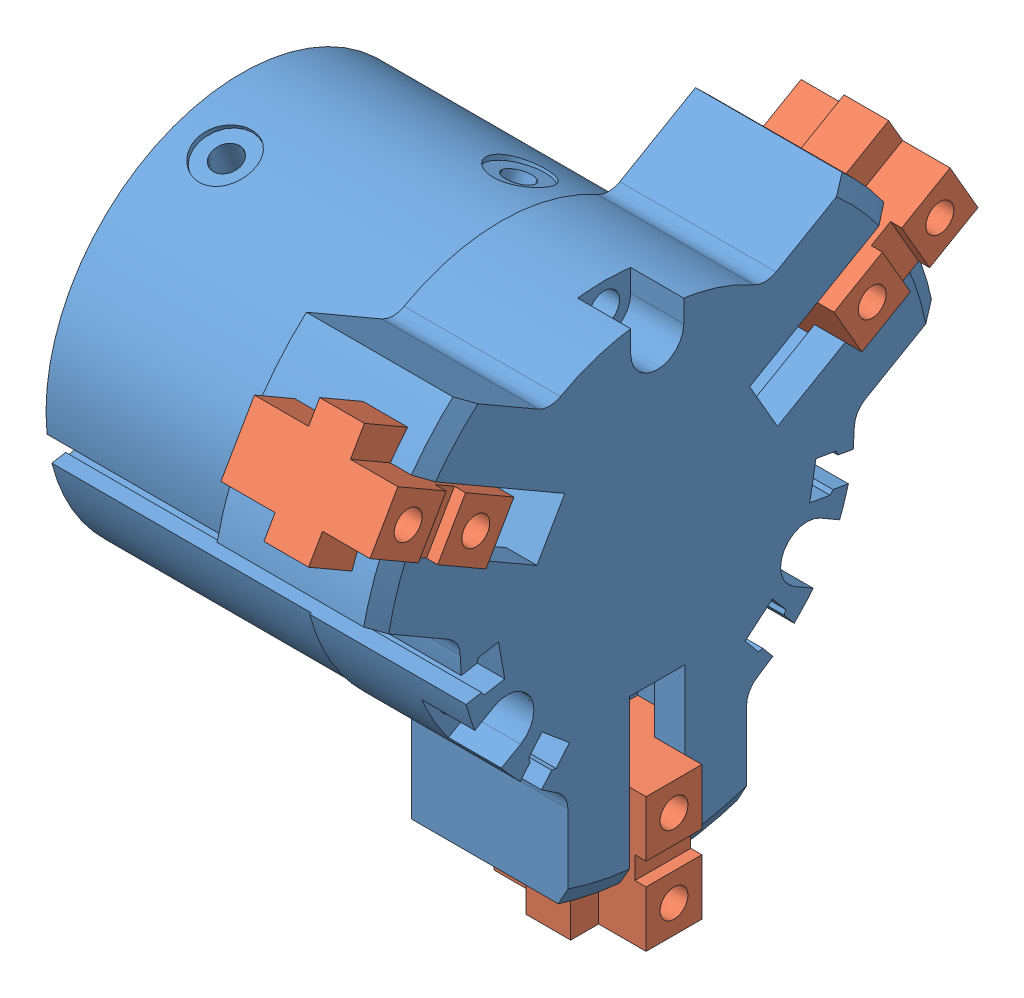
SolidWorks assembly MHSL3-50D, configuration MHSL3-50D. Lengths in mm.
Overall size (77.5 98.66 113.92).
4 component instances, 2 part files, 7 mates.
Components (placement in the parent):
- MHSL3-50D_MHSL-Body-1: MHSL3-50D_MHSL-Body [50] x (-1 0 0) z (0 0 -1) size (74.5 90.6 101.7)
- MHSL3-50D_MHSL-Finger-1: MHSL3-50D_MHSL-Finger [50] at (61 -48 0) x (-1 0 0) z (0 0 1) size (26.2 24 20)
- MHSL3-50D_MHSL-Finger-2: MHSL3-50D_MHSL-Finger [50] at (61 24 41.5692) x (-1 0 0) z (0 0.866025 -0.5) size (26.2 24 20)
- MHSL3-50D_MHSL-Finger-3: MHSL3-50D_MHSL-Finger [50] at (61 24 -41.5692) x (-1 0 0) z (0 -0.866025 -0.5) size (26.2 24 20)
Mates (geometry in assembly coordinates):
- Coincident1: coincident: plane of MHSL3-50D_MHSL-Body-1 through (0 0 0) normal (-1 0 0); plane of assembly through (0 0 0) normal (1 0 0)
- Coincident2: coincident: plane of MHSL3-50D_MHSL-Body-1 through (0 0 0) normal (0 1 0); plane of assembly through (0 0 0) normal (0 1 0)
- Coincident3: coincident: plane of MHSL3-50D_MHSL-Body-1 through (0 0 0) normal (0 0 -1); plane of assembly through (0 0 0) normal (0 0 1)
- Coincident4: coincident: plane of MHSL3-50D_MHSL-Body-1 through (61 -22 5) normal (1 0 0); plane of MHSL3-50D_MHSL-Finger-1 through (61 -60 5) normal (-1 0 0)
- Coincident6: coincident: plane of MHSL3-50D_MHSL-Body-1 through (0 0 0) normal (0 0 -1); plane of MHSL3-50D_MHSL-Finger-1 through (61 -48 0) normal (0 0 1)
- DO(GripperOpen): distance = 60 mm: plane of MHSL3-50D_MHSL-Body-1 through (0 0 0) normal (0 1 0); plane of MHSL3-50D_MHSL-Finger-1 through (77.5 -60 5) normal (0 -1 0)
- DC(GripperClose): distance = 46 mm: plane of ? through (58 -42 4) normal (0 -1 0)
